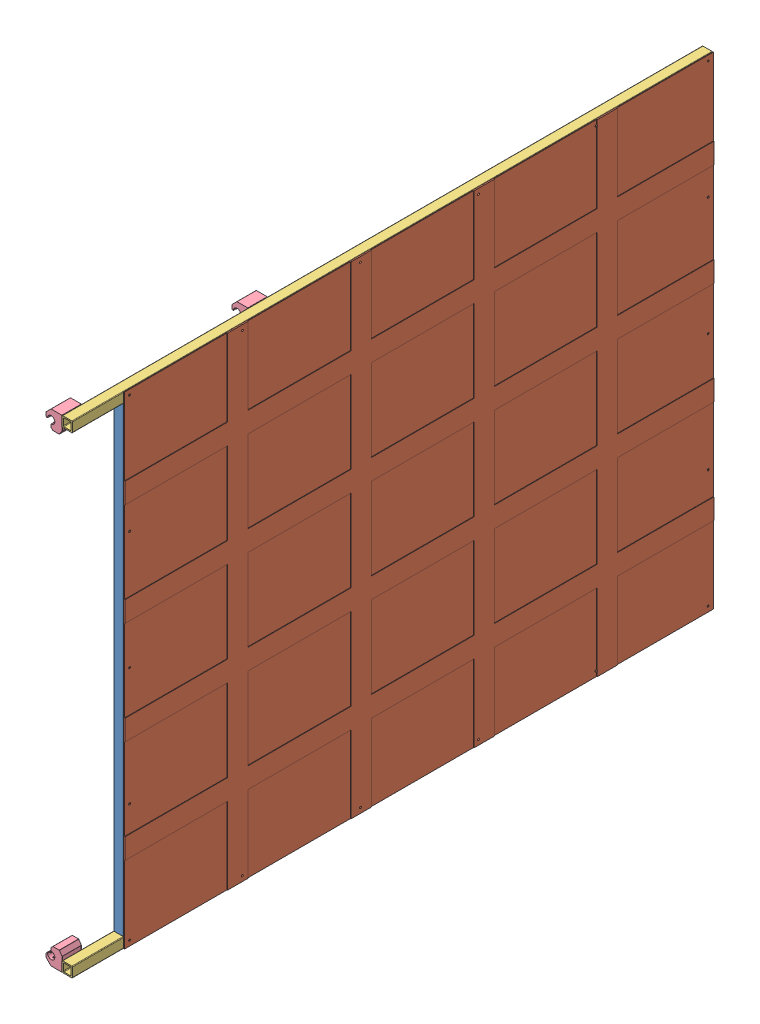
SolidWorks assembly GE-16165_ASM, configuration Default. Lengths in mm.
Overall size (68.08 1193.8 1584.33).
9 component instances, 4 part files, 0 mates.
Components (placement in the parent):
- GE-16166-01-1: GE-16166-01 [Default] at origin size (25.4 1143 25.4)
- GE-16167-1: GE-16167 [Default] at (15.875 571.5 715.9625) x (0 -1 0) z (-1 0 0) size (1193.8 1457.33 3.18)
- GE-16166-02-1: GE-16166-02 [Default] at (0 1155.7 -12.7) x (1 0 0) z (0 -1 0) size (25.4 1584.33 25.4)
- GE-16166-02-2: GE-16166-02 [Default] at (0 -12.7 -12.7) x (-1 0 0) z (0 1 0) size (25.4 1584.33 25.4)
- GE-16166-01-2: GE-16166-01 [Default] at (0 1143 1431.925) x (1 0 0) z (0 0 -1) size (25.4 1143 25.4)
- GE-16168-1: GE-16168 [Default] at (-39.7 -2.4 1523.625) x (0 1 0) z (1 0 0) size (44 48 39.5)
- GE-16168-2: GE-16168 [Default] at (-39.7 -2.4 1063.625) x (0 1 0) z (1 0 0) size (44 48 39.5)
- GE-16168-3: GE-16168 [Default] at (-39.7 1145.4 1571.625) x (0 -1 0) z (1 0 0) size (44 48 39.5)
- GE-16168-4: GE-16168 [Default] at (-39.7 1145.4 1111.625) x (0 -1 0) z (1 0 0) size (44 48 39.5)
